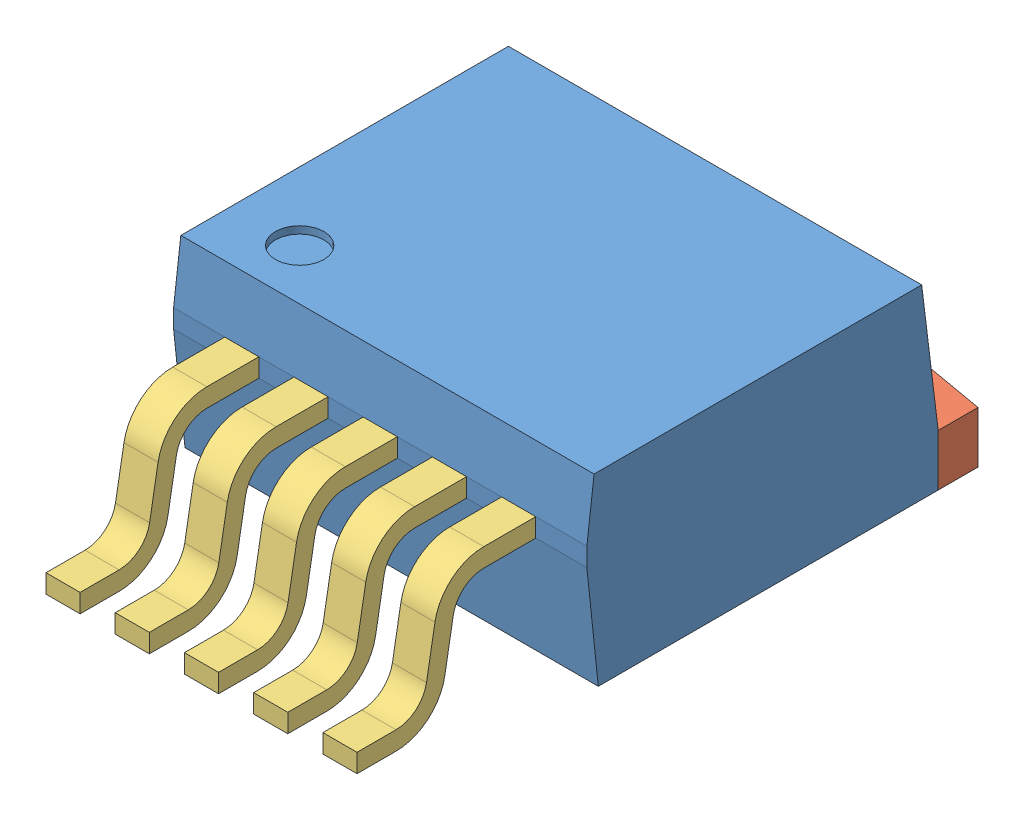
SolidWorks assembly KTT0005B, configuration Default. Lengths in mm.
Overall size (10.16 4.72 14.3).
7 component instances, 3 part files, 0 mates.
Components (placement in the parent):
- BODY_TS5B-1: BODY_TS5B [Default] at (0 0 -3.556) size (10.16 4.57 8.64)
- HTSINK_TS5B-1: HTSINK_TS5B [Default] at origin size (10.16 1.27 8.89)
- LEAD_TS5B-1: LEAD_TS5B [Default] at (3.4036 0.6096 11.049) size (0.84 3.28 4.39)
- LEAD_TS5B-2: LEAD_TS5B [Default] at (1.7018 0.6096 11.049) size (0.84 3.28 4.39)
- LEAD_TS5B-3: LEAD_TS5B [Default] at (0 0.6096 11.049) size (0.84 3.28 4.39)
- LEAD_TS5B-4: LEAD_TS5B [Default] at (-1.7018 0.6096 11.049) size (0.84 3.28 4.39)
- LEAD_TS5B-5: LEAD_TS5B [Default] at (-3.4036 0.6096 11.049) size (0.84 3.28 4.39)
